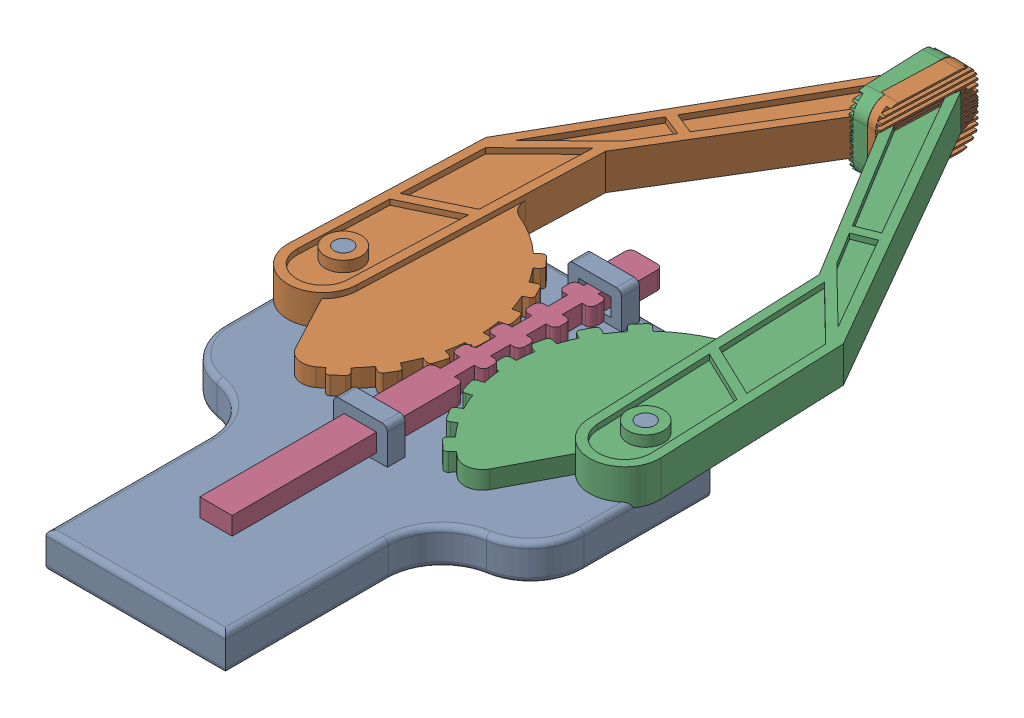
SolidWorks assembly robotic arm clipper, configuration Default. Lengths in mm.
Overall size (211.01 47 463.25).
4 component instances, 3 part files, 15 mates.
Components (placement in the parent):
- base part 1-1: base part 1 [Default] at (71.4468 5.139 61.5758) x (1 0 0) z (0 1 0) size (200 270 40)
- Part3-1: Part3 [Default] at (69.9727 32.139 -135.9353) x (0.999342 0 0.036276) z (0 1 0) size (103.8 323.33 40)
- Part3-2: Part3 [Default] at (72.176 32.139 -135.6503) x (-0.999212 0 0.0397) z (0 -1 0) size (103.8 323.33 40)
- Part2-2: Part2 [Default] at (71.4468 39.139 -3.18) x (1 0 0) z (0 -1 0) size (18 240 10)
Mates (geometry in assembly coordinates):
- Concentric1: concentric: cylinder of base part 1-1 through (-12.8232 45.139 81.5758) axis (0 -1 0) radius 5; cylinder of Part3-1 through (-12.8232 45.139 81.5758) axis (0 -1 0) radius 5
- Coincident1: coincident: plane of base part 1-1 through (71.4468 25.139 61.5758) normal (0 1 0); plane of Part3-1 through (69.5488 25.139 -136.0962) normal (0 -1 0)
- Concentric2: concentric: cylinder of base part 1-1 through (155.7168 45.139 81.5758) axis (0 -1 0) radius 5; cylinder of Part3-2 through (155.7168 19.139 81.5758) axis (0 1 0) radius 5
- Coincident2: coincident: plane of base part 1-1 through (71.4468 25.139 61.5758) normal (0 1 0); plane of Part3-2 through (72.6203 25.139 -135.8207) normal (0 -1 0)
- GearMate1: gear = 150 : 150 mm: cylinder of Part3-1 through (-12.8232 29.139 81.5758) axis (0 1 0) radius 75; cylinder of Part3-2 through (155.7168 35.139 81.5758) axis (0 -1 0) radius 75
- LimitAngle5: limit planar angle = 0.523599 rad aligned: plane of Part3-2 through (135.5336 22.139 92.9282) normal (-0.999977 0 -0.006756); plane of Part3-1 through (7.374 42.139 92.9032) normal (0.999968 0 -0.007994)
- Coincident5: coincident: plane of base part 1-1 through (80.4468 39.139 11.5758) normal (-1 0 0); plane of Part2-2 through (80.4468 29.139 116.82) normal (1 0 0)
- Coincident6: coincident: plane of base part 1-1 through (62.4468 29.139 11.5758) normal (0 1 0); plane of Part2-2 through (71.4468 29.139 -3.18) normal (0 -1 0)
- GearMate2: gear = 6 : 4 mm: cylinder of Part3-1 through (63.6835 29.139 66.2545) axis (0 1 0) radius 2; cylinder of Part2-2 through (65.4468 29.139 70.82) axis (0 1 0) radius 3
- GearMate3: gear = 6 : 4 mm: cylinder of Part3-2 through (79.158 35.139 66.5168) axis (0 -1 0) radius 2; cylinder of Part2-2 through (77.4468 29.139 70.82) axis (0 1 0) radius 3
- GearMate4: gear = 4 : 6 mm: cylinder of Part2-2 through (65.4468 29.139 50.82) axis (0 1 0) radius 3; cylinder of Part3-1 through (57.1112 29.139 46.9752) axis (0 1 0) radius 2
- GearMate5: gear = 4 : 6 mm: cylinder of Part2-2 through (77.4468 29.139 50.82) axis (0 1 0) radius 3; cylinder of Part3-2 through (85.6643 35.139 47.215) axis (0 -1 0) radius 2
- GearMate6: gear = 6 : 4 mm: cylinder of Part3-1 through (65.042 29.139 86.578) axis (0 1 0) radius 2; cylinder of Part2-2 through (65.4468 29.139 90.82) axis (0 1 0) radius 3
- GearMate7: gear = 4 : 6 mm: cylinder of Part2-2 through (77.4468 29.139 90.82) axis (0 1 0) radius 3; cylinder of Part3-2 through (77.8691 35.139 86.8448) axis (0 -1 0) radius 2
- GearMate8: gear = 1 : 1 mm: cylinder of Part3-1 through (65.042 29.139 86.578) axis (0 1 0) radius 2; cylinder of Part2-2 through (65.4468 29.139 90.82) axis (0 1 0) radius 3
